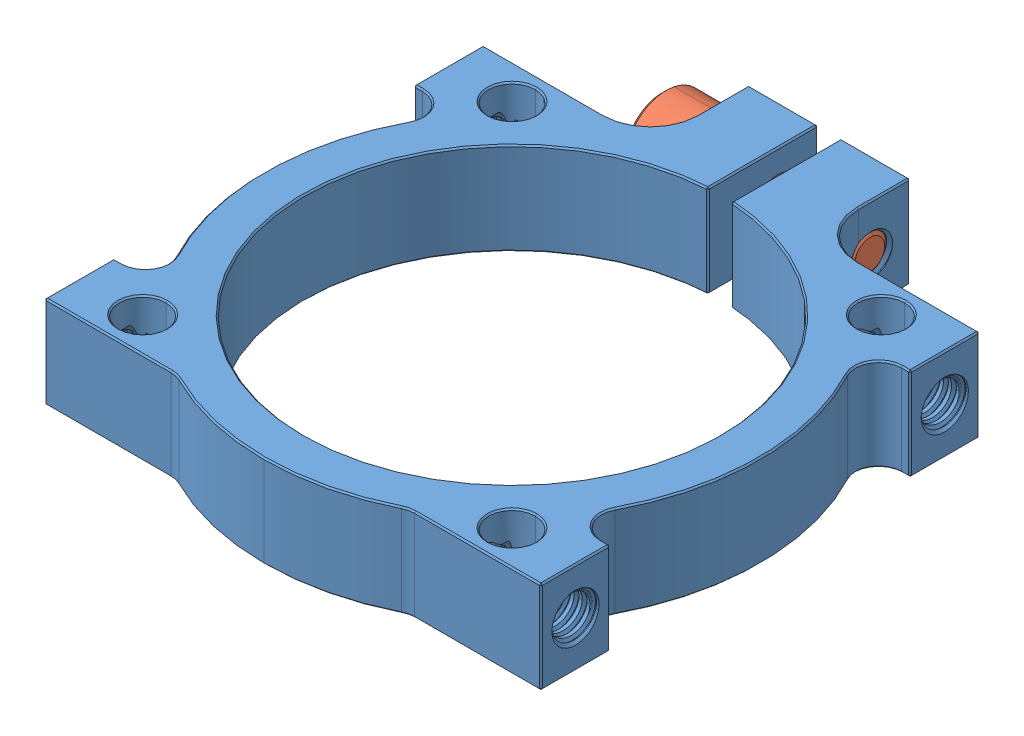
SolidWorks assembly 2-Side, 2-Post Clamping Mount (43mm Width, 36mm Bore)1401-0043-0036, configuration Default. Lengths in mm.
Overall size (43 8.28 49.64).
2 component instances, 2 part files, 0 mates.
Components (placement in the parent):
- 1401-0043-0036.STEP-1: 1401-0043-0036.STEP [Default] at (-33.7112 6.5261 16.3552) size (43 8 49)
- 2800-0004-0014_90128A207.STEP-1: 2800-0004-0014_90128A207.STEP [Default] at (-26.7112 6.5261 -7.6448) x (0 -0.97891 0.204292) z (1 0 0) size (7 7 18.01)
